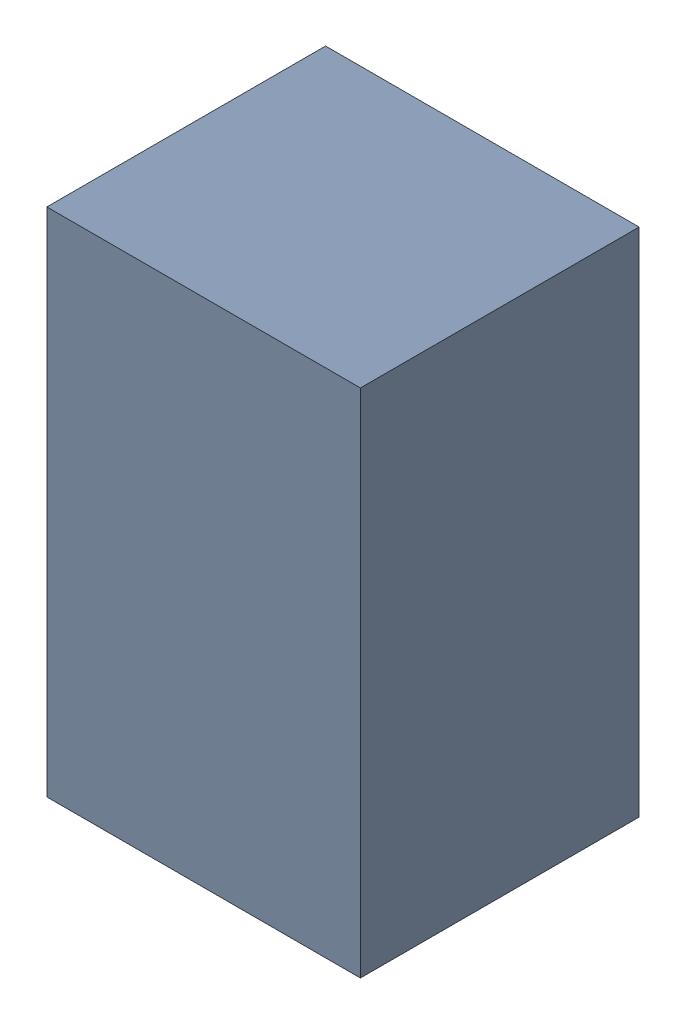
SolidWorks assembly C5, configuration Default. Lengths in mm.
Overall size (1.35 2.2 1.2).
2 component instances, 1 part files, 0 mates.
Components (placement in the parent):
- 407985568-1: 407985568 [Default] at (25.781 43.307 0.0127) size (1.35 2.2 1.2)
  - Extruded_3-1: Extruded_3 [Default] at origin size (1.35 2.2 1.2)
